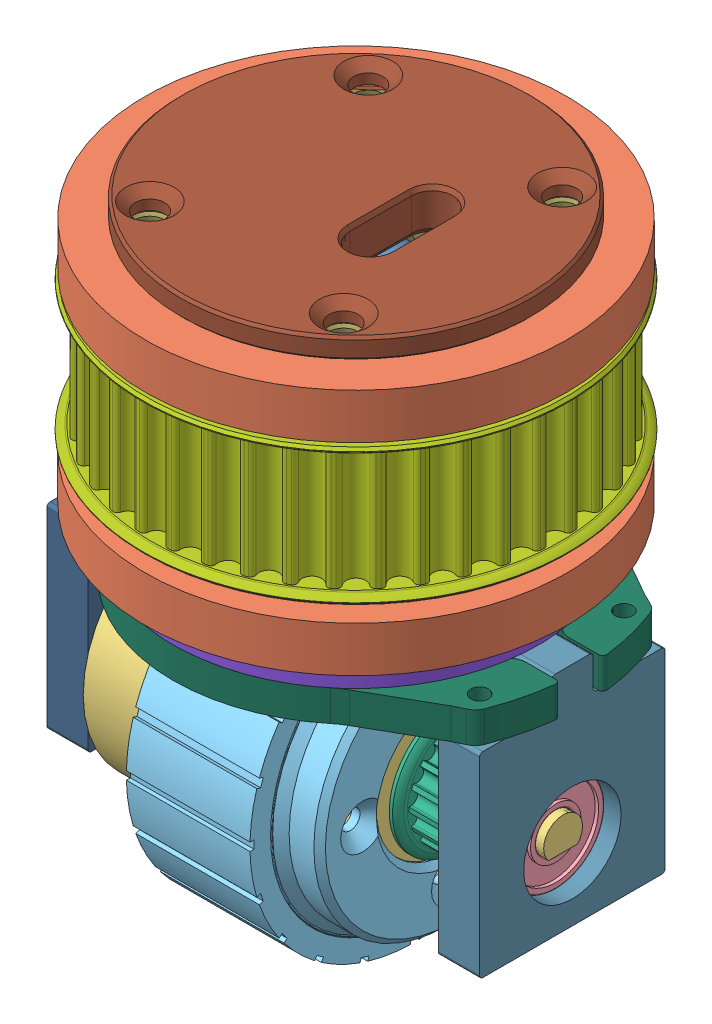
SolidWorks assembly Manufacture Ready Swerve_Double Gearbox Wheel_Assem, configuration Default. Lengths in mm.
Overall size (83.94 95.24 79.69).
18 component instances, 16 part files, 49 mates.
Components (placement in the parent):
- PROPDRIVE 2836-1: PROPDRIVE 2836 [Default] at (-7.34 47.9628 0) x (0 0.80165 -0.597794) z (0 0.597794 0.80165) size (28 45.1 28)
- Zoro Bearing 50mmID 65mm OD 7mmWidth-1: Zoro Bearing 50mmID 65mm OD 7mmWidth [Default] at (0 63.175 0) x (0.965482 0 -0.260469) z (0.260469 0 0.965482) size (65 7 65)
- Zoro Bearing 50mmID 65mm OD 7mmWidth-2: Zoro Bearing 50mmID 65mm OD 7mmWidth [Default] at (0 32.075 0) x (0.000165 0 -1) z (1 0 0.000165) size (65 7 65)
- Double Gearbox 36mm 19 to 1-2: Double Gearbox 36mm 19 to 1 [Default] at (-6.0895 0 0) x (0 0 1) z (0 1 0) size (36 76.01 36)
- FL696ZZ-1: FL696ZZ [Default] at (30.7875 0 0) x (-1 0 0) z (0 -0.99717 0.07518) size (5 17 17)
- Casted Swerve Wheel-1: Casted Swerve Wheel [Just Wheel] at (-0.4634 0 0) size (26.13 50.78 50.78)
- Custom Input Shaft Pully-3: Custom Input Shaft Pully [Default] at (20.1995 0 0) x (0 0 1) z (0 1 0) size (19.98 11.18 19.98)
- 5mm Pully Interface-1: 5mm Pully Interface [Default] at origin size (65.57 21.67 65.57)
- Bottom Bearing Retainer-1: Bottom Bearing Retainer [Default] at origin size (56.35 4.76 56.35)
- Drive Motor Face Mount-1: Drive Motor Face Mount [Default] at origin size (2.29 27.26 43.18)
- Gearbox-Side Support-1: Gearbox-Side Support [Default] at origin size (6.35 34.92 28.57)
- Inner Modual Lid-1: Inner Modual Lid [Default] at origin size (53.98 6.35 53.98)
- Innermost Structure-1: Innermost Structure [Default] at origin size (50.34 38.64 53.98)
- Left Motor Mount Retainer-1: Left Motor Mount Retainer [Default] at origin size (10.68 17.78 8.44)
- Pully-Side Support-1: Pully-Side Support [Default] at origin size (6.35 34.92 28.57)
- Wheel Support Mount Plate-1: Wheel Support Mount Plate [Default] at origin size (69.4 4.76 56.35)
- Left Motor Mount Retainer-2: Left Motor Mount Retainer [Right] at origin size (10.68 17.78 8.44)
- Custom Motor Output Shaft Pinion-3: Custom Motor Output Shaft Pinion [Default] at (19.5645 47.9628 0) x (0 -0.974186 0.225748) z (0 0.225748 0.974186) size (16.43 12.7 16.28)
Mates (geometry in assembly coordinates):
- Concentric30: concentric aligned: cylinder of Double Gearbox 36mm 19 to 1-2 through (11.8556 0 0) axis (-1 0 0) radius 18; cylinder of Casted Swerve Wheel-1 through (9.0616 0 0) axis (-1 0 0) radius 18
- Coincident40: coincident anti-aligned: plane of Double Gearbox 36mm 19 to 1-2 through (11.8556 0 0) normal (1 0 0); plane of Casted Swerve Wheel-1 through (11.8556 0 0) normal (-1 0 0)
- Concentric31: concentric aligned: cylinder of Double Gearbox 36mm 19 to 1-2 through (7.8556 0 14) axis (1 0 0) radius 1.5; cylinder of Casted Swerve Wheel-1 through (-9.9884 0 14) axis (1 0 0) radius 1.5
- Concentric32: concentric aligned: cylinder of Double Gearbox 36mm 19 to 1-2 through (31.913 0 0) axis (-1 0 0) radius 3; cylinder of Custom Input Shaft Pully-1 through (25.7875 0 0) axis (-1 0 0) radius 3.302
- Parallel2: parallel anti-aligned: plane of Double Gearbox 36mm 19 to 1-2 through (16.913 -2 -2.2361) normal (0 -1 0); plane of Custom Input Shaft Pully-1 through (11.0555 -2.794 -1.7598) normal (0 1 0)
- Coincident42: coincident anti-aligned: plane of FL696ZZ-1 through (25.7875 -3.5958 4.1822) normal (-1 0 0); plane of Custom Input Shaft Pully-1 through (25.7875 0 0) normal (1 0 0)
- Coincident43: coincident aligned: plane of Bottom Bearing Retainer-1 through (0 0 0) normal (0 0 1)
- Coincident44: coincident aligned: plane of Bottom Bearing Retainer-1 through (0 0 0) normal (0 1 0)
- Coincident45: coincident aligned: plane of Bottom Bearing Retainer-1 through (0 0 0) normal (1 0 0)
- Coincident46: coincident aligned: plane of Drive Motor Face Mount-1 through (0 0 0) normal (0 0 1)
- Coincident47: coincident aligned: plane of Drive Motor Face Mount-1 through (0 0 0) normal (0 1 0)
- Coincident48: coincident aligned: plane of Drive Motor Face Mount-1 through (0 0 0) normal (1 0 0)
- Coincident49: coincident aligned: plane of Gearbox-Side Support-1 through (0 0 0) normal (0 0 1)
- Coincident50: coincident aligned: plane of Gearbox-Side Support-1 through (0 0 0) normal (0 1 0)
- Coincident51: coincident aligned: plane of Gearbox-Side Support-1 through (0 0 0) normal (1 0 0)
- Coincident52: coincident aligned: plane of Inner Modual Lid-1 through (0 0 0) normal (0 0 1)
- Coincident53: coincident aligned: plane of Inner Modual Lid-1 through (0 0 0) normal (0 1 0)
- Coincident54: coincident aligned: plane of Inner Modual Lid-1 through (0 0 0) normal (1 0 0)
- Coincident55: coincident aligned: plane of Innermost Structure-1 through (0 0 0) normal (0 0 1)
- Coincident56: coincident aligned: plane of Innermost Structure-1 through (0 0 0) normal (0 1 0)
- Coincident57: coincident aligned: plane of Innermost Structure-1 through (0 0 0) normal (1 0 0)
- Coincident58: coincident aligned: plane of Left Motor Mount Retainer-1 through (0 0 0) normal (0 0 1)
- Coincident59: coincident aligned: plane of Left Motor Mount Retainer-1 through (0 0 0) normal (0 1 0)
- Coincident60: coincident aligned: plane of Left Motor Mount Retainer-1 through (0 0 0) normal (1 0 0)
- Coincident61: coincident aligned: plane of Pully-Side Support-1 through (0 0 0) normal (0 0 1)
- Coincident62: coincident aligned: plane of Pully-Side Support-1 through (0 0 0) normal (0 1 0)
- Coincident63: coincident aligned: plane of Pully-Side Support-1 through (0 0 0) normal (1 0 0)
- Coincident67: coincident aligned: plane of Wheel Support Mount Plate-1 through (0 0 0) normal (0 0 1)
- Coincident68: coincident aligned: plane of Wheel Support Mount Plate-1 through (0 0 0) normal (0 1 0)
- Coincident69: coincident aligned: plane of Wheel Support Mount Plate-1 through (0 0 0) normal (1 0 0)
- Coincident70: coincident aligned: plane of 5mm Pully Interface-1 through (0 0 0) normal (0 0 1)
- Coincident71: coincident aligned: plane of 5mm Pully Interface-1 through (0 0 0) normal (0 1 0)
- Coincident72: coincident aligned: plane of 5mm Pully Interface-1 through (0 0 0) normal (1 0 0)
- Concentric33: concentric aligned: cylinder of Zoro Bearing 50mmID 65mm OD 7mmWidth-1 through (0 66.675 0) axis (0 -1 0) radius 25; cylinder of Innermost Structure-1 through (0 66.675 0) axis (0 -1 0) radius 24.8984
- Coincident73: coincident anti-aligned: plane of Zoro Bearing 50mmID 65mm OD 7mmWidth-1 through (0 66.675 0) normal (0 1 0); plane of Inner Modual Lid-1 through (0 66.675 0) normal (0 -1 0)
- Concentric34: concentric anti-aligned: cylinder of Zoro Bearing 50mmID 65mm OD 7mmWidth-2 through (0 35.575 0) axis (0 -1 0) radius 25; cylinder of Innermost Structure-1 through (0 28.575 0) axis (0 1 0) radius 24.8984
- Concentric35: concentric anti-aligned: cylinder of Double Gearbox 36mm 19 to 1-2 through (-44.092 0 0) axis (1 0 0) radius 4; cylinder of Gearbox-Side Support-1 through (-26.9875 0 0) axis (-1 0 0) radius 4.0127
- Concentric36: concentric anti-aligned: cylinder of FL696ZZ-1 through (15.7875 0 0) axis (-1 0 0) radius 7.5; cylinder of Pully-Side Support-1 through (-34.7814 0 0) axis (1 0 0) radius 7.5
- Coincident75: coincident anti-aligned: plane of FL696ZZ-1 through (26.9875 9.1324 8.0685) normal (1 0 0); plane of Pully-Side Support-1 through (26.9875 -11.1125 -12.7) normal (-1 0 0)
- Concentric37: concentric anti-aligned: cylinder of PROPDRIVE 2836-1 through (-24.84 47.9628 0) axis (1 0 0) radius 14; cylinder of Drive Motor Face Mount-1 through (12.446 47.9628 0) axis (-1 0 0) radius 4.7625
- Coincident76: coincident anti-aligned: plane of PROPDRIVE 2836-1 through (10.16 47.9628 0) normal (1 0 0); plane of Drive Motor Face Mount-1 through (10.16 47.9628 0) normal (-1 0 0)
- Coincident77: coincident anti-aligned: plane of Double Gearbox 36mm 19 to 1-2 through (14.6115 0 0) normal (1 0 0); plane of Custom Input Shaft Pully-1 through (14.6115 0 0) normal (-1 0 0)
- Parallel3: parallel aligned: plane of Double Gearbox 36mm 19 to 1-2 through (-20.7068 -3 -2.6458) normal (0 -1 0); plane of Gearbox-Side Support-1 through (0 -11.1125 0) normal (0 -1 0)
- Coincident79: coincident aligned: plane of Left Motor Mount Retainer-2 through (0 0 0) normal (0 0 1)
- Coincident80: coincident aligned: plane of Left Motor Mount Retainer-2 through (0 0 0) normal (0 1 0)
- Coincident81: coincident aligned: plane of Left Motor Mount Retainer-2 through (0 0 0) normal (1 0 0)
- Coincident82: coincident anti-aligned: plane of Zoro Bearing 50mmID 65mm OD 7mmWidth-2 through (0 28.575 0) normal (0 -1 0); plane of Bottom Bearing Retainer-1 through (0 28.575 0) normal (0 1 0)
- Concentric39: concentric aligned: cylinder of PROPDRIVE 2836-1 through (69.8501 47.9628 0) axis (-1 0 0) radius 1.5875; cylinder of Custom Motor Output Shaft Pinion-3 through (27.1845 47.9628 0) axis (-1 0 0) radius 1.5625
- Distance1: distance = 1.905 mm anti-aligned: plane of Custom Motor Output Shaft Pinion-3 through (25.9145 55.4407 -11.989) normal (1 0 0); plane of Custom Input Shaft Pully-3 through (24.0095 0 0) normal (-1 0 0)
